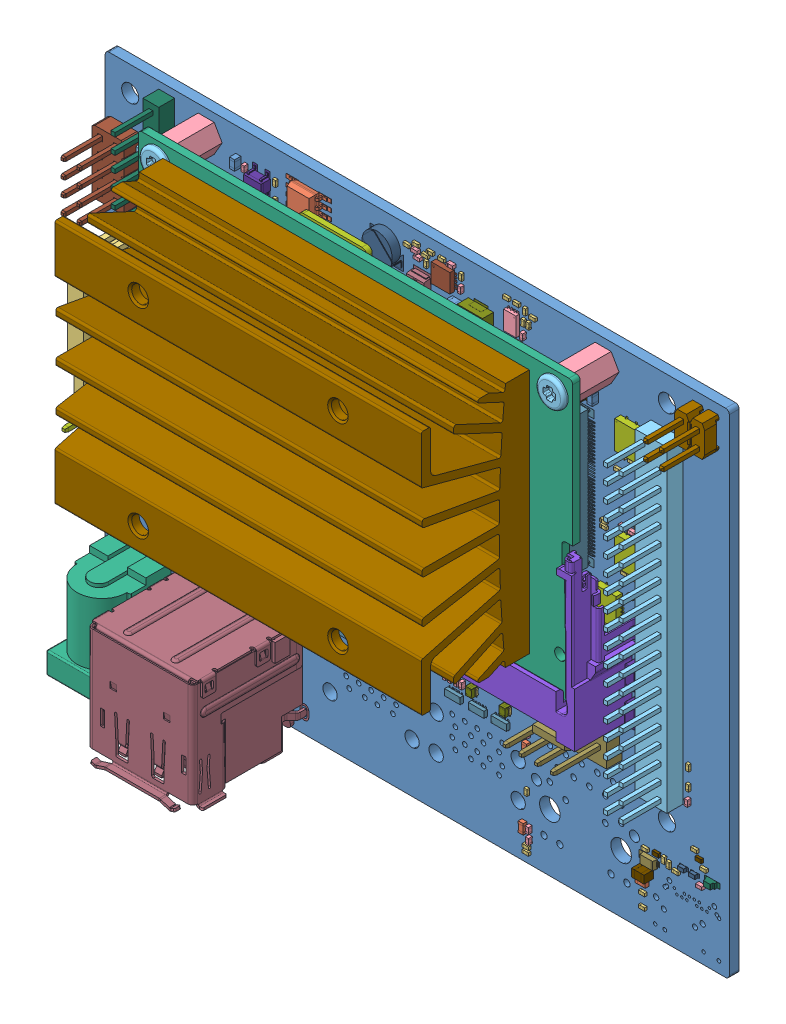
SolidWorks assembly P3450_P3449_A02_P3448_A02, configuration Défaut. Lengths in mm.
Overall size (100 81.03 30.21).
395 component instances, 66 part files, 0 mates.
Components (placement in the parent):
- 142-13449-1000-A02_ASM-1: 142-13449-1000-A02_ASM [Défaut] at origin size (100 81.03 22.88)
  - 142-13449-1000-A02-1: 142-13449-1000-A02 [Défaut] at origin size (100 79 1.57)
  - 315-1109-000_1-1: 315-1109-000_1 [Défaut] at (5.6 4.9 1.575) x (-1 0 0) z (0 0 1) size (4.5 3.5 0.8)
  - 0402_H040-1: 0402_H040 [Défaut] at (8 -0.825 1.575) size (1 0.5 0.4)
  - 0402_H060-1: 0402_H060 [Défaut] at (1 5 1.575) x (0 -1 0) z (0 0 1) size (1 0.5 0.6)
  - 0402_H040-2: 0402_H040 [Défaut] at (9.9 -0.3 1.575) size (1 0.5 0.4)
  - 0402_H040-3: 0402_H040 [Défaut] at (8.296 51.194 1.575) x (-1 0 0) z (0 0 1) size (1 0.5 0.4)
  - 0402_H040-4: 0402_H040 [Défaut] at (76.2 36.9 1.575) x (-1 0 0) z (0 0 1) size (1 0.5 0.4)
  - 0402_H040-5: 0402_H040 [Défaut] at (37.8 2.87 1.575) x (0 -1 0) z (0 0 1) size (1 0.5 0.4)
  - 0402_H040-6: 0402_H040 [Défaut] at (38.6 2.87 1.575) x (0 -1 0) z (0 0 1) size (1 0.5 0.4)
  - 0402_H060-2: 0402_H060 [Défaut] at (14.2 7.7 1.575) x (0 -1 0) z (0 0 1) size (1 0.5 0.6)
  - 0402_H040-7: 0402_H040 [Défaut] at (64 27.5 1.575) x (-1 0 0) z (0 0 1) size (1 0.5 0.4)
  - 0402_H060-3: 0402_H060 [Défaut] at (18.6 43.15 1.575) x (-1 0 0) z (0 0 1) size (1 0.5 0.6)
  - 0402_H060-4: 0402_H060 [Défaut] at (65.5 52.8 1.575) x (0 1 0) z (0 0 1) size (1 0.5 0.6)
  - 0402_H060-5: 0402_H060 [Défaut] at (64 28.4 1.575) x (-1 0 0) z (0 0 1) size (1 0.5 0.6)
  - 0402_H040-8: 0402_H040 [Défaut] at (60.95 25.85 1.575) size (1 0.5 0.4)
  - 0402_H060-6: 0402_H060 [Défaut] at (17.3 7.7 1.575) x (0 -1 0) z (0 0 1) size (1 0.5 0.6)
  - 0402_H060-7: 0402_H060 [Défaut] at (18.6 7.7 1.575) x (0 -1 0) z (0 0 1) size (1 0.5 0.6)
  - 0402_H060-8: 0402_H060 [Défaut] at (12.9 7.7 1.575) x (0 -1 0) z (0 0 1) size (1 0.5 0.6)
  - 0402_H060-9: 0402_H060 [Défaut] at (80.9 37.7 1.575) x (-1 0 0) z (0 0 1) size (1 0.5 0.6)
  - 0402_H040-9: 0402_H040 [Défaut] at (79.5 31.3 1.575) size (1 0.5 0.4)
  - 0402_H040-10: 0402_H040 [Défaut] at (81 31.3 1.575) x (-1 0 0) z (0 0 1) size (1 0.5 0.4)
  - 0402_H060-10: 0402_H060 [Défaut] at (79.3 37.7 1.575) size (1 0.5 0.6)
  - 0402_H060-11: 0402_H060 [Défaut] at (74.8 4.05 1.575) x (-1 0 0) z (0 0 1) size (1 0.5 0.6)
  - 0402_H040-11: 0402_H040 [Défaut] at (65.675 6.15 1.575) x (0 -1 0) z (0 0 1) size (1 0.5 0.4)
  - 0402_H060-12: 0402_H060 [Défaut] at (67.7 6.85 1.575) x (0 1 0) z (0 0 1) size (1 0.5 0.6)
  - 0402_H040-12: 0402_H040 [Défaut] at (64.475 5.8 1.575) x (-1 0 0) z (0 0 1) size (1 0.5 0.4)
  - 0402_H040-13: 0402_H040 [Défaut] at (67.725 5.325 1.575) x (0 1 0) z (0 0 1) size (1 0.5 0.4)
  - 0402_H060-13: 0402_H060 [Défaut] at (46.1 59.45 1.575) size (1 0.5 0.6)
  - 0402_H040-14: 0402_H040 [Défaut] at (44.65 59.45 1.575) size (1 0.5 0.4)
  - 0402_H040-15: 0402_H040 [Défaut] at (46.1 60.25 1.575) size (1 0.5 0.4)
  - 0402_H060-14: 0402_H060 [Défaut] at (53.35 57.7 1.575) x (0 -1 0) z (0 0 1) size (1 0.5 0.6)
  - 0402_H040-16: 0402_H040 [Défaut] at (47.6 59.45 1.575) size (1 0.5 0.4)
  - 0402_H040-17: 0402_H040 [Défaut] at (48.4 60.25 1.575) size (1 0.5 0.4)
  - 0402_H040-18: 0402_H040 [Défaut] at (47.7 58.325 1.575) x (0 1 0) z (0 0 1) size (1 0.5 0.4)
  - 0402_H060-15: 0402_H060 [Défaut] at (46.5 58.65 1.575) x (-1 0 0) z (0 0 1) size (1 0.5 0.6)
  - 0402_H060-16: 0402_H060 [Défaut] at (51.8 60.25 1.575) size (1 0.5 0.6)
  - 0402_H040-19: 0402_H040 [Défaut] at (53.35 59.4 1.575) x (0 -1 0) z (0 0 1) size (1 0.5 0.4)
  - 0402_H040-20: 0402_H040 [Défaut] at (50.2 60.25 1.575) x (-1 0 0) z (0 0 1) size (1 0.5 0.4)
  - 0402_H060-17: 0402_H060 [Défaut] at (18.6 43.95 1.575) x (-1 0 0) z (0 0 1) size (1 0.5 0.6)
  - 0402_H060-18: 0402_H060 [Défaut] at (52.75 2.9 1.575) x (0 -1 0) z (0 0 1) size (1 0.5 0.6)
  - 0402_H060-19: 0402_H060 [Défaut] at (22.35 47.4 1.575) x (-1 0 0) z (0 0 1) size (1 0.5 0.6)
  - 0402_H060-20: 0402_H060 [Défaut] at (20.55 47.4 1.575) x (-1 0 0) z (0 0 1) size (1 0.5 0.6)
  - 0402_H060-21: 0402_H060 [Défaut] at (21.95 34.55 1.575) x (0 -1 0) z (0 0 1) size (1 0.5 0.6)
  - 0402_H060-22: 0402_H060 [Défaut] at (21.05 34.55 1.575) x (0 -1 0) z (0 0 1) size (1 0.5 0.6)
  - 0402_H060-23: 0402_H060 [Défaut] at (53.55 2.9 1.575) x (0 -1 0) z (0 0 1) size (1 0.5 0.6)
  - 0402_H060-24: 0402_H060 [Défaut] at (25.4 54 1.575) x (-1 0 0) z (0 0 1) size (1 0.5 0.6)
  - 0402_H060-25: 0402_H060 [Défaut] at (24 34.58 1.575) x (0 -1 0) z (0 0 1) size (1 0.5 0.6)
  - 0402_H040-21: 0402_H040 [Défaut] at (55.6 2.95 1.575) x (0 -1 0) z (0 0 1) size (1 0.5 0.4)
  - 0402_H040-22: 0402_H040 [Défaut] at (20.13 34.53 1.575) x (0 1 0) z (0 0 1) size (1 0.5 0.4)
  - 0402_H060-26: 0402_H060 [Défaut] at (18.4 35.15 1.575) x (0 1 0) z (0 0 1) size (1 0.5 0.6)
  - 0402_H060-27: 0402_H060 [Défaut] at (18.4 36.75 1.575) x (0 1 0) z (0 0 1) size (1 0.5 0.6)
  - 0402_H040-23: 0402_H040 [Défaut] at (39.6 2.87 1.575) x (0 -1 0) z (0 0 1) size (1 0.5 0.4)
  - 0402_H040-24: 0402_H040 [Défaut] at (40.4 2.87 1.575) x (0 -1 0) z (0 0 1) size (1 0.5 0.4)
  - 0402_H040-25: 0402_H040 [Défaut] at (60.95 2.95 1.575) x (0 -1 0) z (0 0 1) size (1 0.5 0.4)
  - 0402_H040-26: 0402_H040 [Défaut] at (60.15 2.95 1.575) x (0 -1 0) z (0 0 1) size (1 0.5 0.4)
  - 0402_H040-27: 0402_H040 [Défaut] at (54.8 2.95 1.575) x (0 -1 0) z (0 0 1) size (1 0.5 0.4)
  - 0402_H040-28: 0402_H040 [Défaut] at (31.6 54 1.575) size (1 0.5 0.4)
  - 0402_H040-29: 0402_H040 [Défaut] at (27.4 54 1.575) size (1 0.5 0.4)
  - 0402_H040-30: 0402_H040 [Défaut] at (29.6 54 1.575) x (-1 0 0) z (0 0 1) size (1 0.5 0.4)
  - 0402_H040-31: 0402_H040 [Défaut] at (63.775 -14.475 1.575) size (1 0.5 0.4)
  - 0402_H040-32: 0402_H040 [Défaut] at (63.775 -15.275 1.575) size (1 0.5 0.4)
  - 0402_H040-33: 0402_H040 [Défaut] at (8.025 41.475 1.575) x (-1 0 0) z (0 0 1) size (1 0.5 0.4)
  - 0402_H060-28: 0402_H060 [Défaut] at (63.95 1.25 1.575) x (0 1 0) z (0 0 1) size (1 0.5 0.6)
  - 0402_H060-29: 0402_H060 [Défaut] at (2.95 54.05 1.575) x (0 1 0) z (0 0 1) size (1 0.5 0.6)
  - 0402_H040-34: 0402_H040 [Défaut] at (92.2 -3.45 1.575) x (-1 0 0) z (0 0 1) size (1 0.5 0.4)
  - 0402_H060-30: 0402_H060 [Défaut] at (32.85 7.7 1.575) x (0 -1 0) z (0 0 1) size (1 0.5 0.6)
  - 0402_H060-31: 0402_H060 [Défaut] at (27.25 7.7 1.575) x (0 -1 0) z (0 0 1) size (1 0.5 0.6)
  - 0402_H060-32: 0402_H060 [Défaut] at (31.25 7.7 1.575) x (0 -1 0) z (0 0 1) size (1 0.5 0.6)
  - 0402_H060-33: 0402_H060 [Défaut] at (28.85 7.7 1.575) x (0 -1 0) z (0 0 1) size (1 0.5 0.6)
  - 0402_H060-34: 0402_H060 [Défaut] at (32.05 7.7 1.575) x (0 -1 0) z (0 0 1) size (1 0.5 0.6)
  - 0402_H060-35: 0402_H060 [Défaut] at (28.05 7.7 1.575) x (0 -1 0) z (0 0 1) size (1 0.5 0.6)
  - 0402_H060-36: 0402_H060 [Défaut] at (30.45 7.7 1.575) x (0 -1 0) z (0 0 1) size (1 0.5 0.6)
  - 0402_H060-37: 0402_H060 [Défaut] at (29.65 7.7 1.575) x (0 -1 0) z (0 0 1) size (1 0.5 0.6)
  - 0402_H060-38: 0402_H060 [Défaut] at (24.65 6.41 1.575) x (0 -1 0) z (0 0 1) size (1 0.5 0.6)
  - 0402_H060-39: 0402_H060 [Défaut] at (25.85 6.41 1.575) x (0 -1 0) z (0 0 1) size (1 0.5 0.6)
  - 0402_H060-40: 0402_H060 [Défaut] at (4.2 36.5 1.575) x (0 1 0) z (0 0 1) size (1 0.5 0.6)
  - 0402_H060-41: 0402_H060 [Défaut] at (89.7 4.7 1.575) x (0 -1 0) z (0 0 1) size (1 0.5 0.6)
  - 0402_H060-42: 0402_H060 [Défaut] at (82.5 3.8 1.575) x (0 -1 0) z (0 0 1) size (1 0.5 0.6)
  - 0402_H060-43: 0402_H060 [Défaut] at (12.65 49.7 1.575) size (1 0.5 0.6)
  - 0402_H060-44: 0402_H060 [Défaut] at (11.2 50.15 1.575) x (0 -1 0) z (0 0 1) size (1 0.5 0.6)
  - 0402_H060-45: 0402_H060 [Défaut] at (26.5 34.55 1.575) x (0 -1 0) z (0 0 1) size (1 0.5 0.6)
  - 0402_H060-46: 0402_H060 [Défaut] at (29.9 34.5 1.575) x (0 -1 0) z (0 0 1) size (1 0.5 0.6)
  - 0402_H060-47: 0402_H060 [Défaut] at (31.7 40.15 1.575) x (0 1 0) z (0 0 1) size (1 0.5 0.6)
  - 0402_H060-48: 0402_H060 [Défaut] at (31.15 42.5 1.575) x (0 1 0) z (0 0 1) size (1 0.5 0.6)
  - 0402_H060-49: 0402_H060 [Défaut] at (19.2 47.05 1.575) x (0 1 0) z (0 0 1) size (1 0.5 0.6)
  - 0402_H060-50: 0402_H060 [Défaut] at (17.95 42 1.575) x (0 -1 0) z (0 0 1) size (1 0.5 0.6)
  - 0402_H060-51: 0402_H060 [Défaut] at (27.3 48.25 1.575) x (0 1 0) z (0 0 1) size (1 0.5 0.6)
  - 0402_H060-52: 0402_H060 [Défaut] at (31.7 37.85 1.575) x (0 -1 0) z (0 0 1) size (1 0.5 0.6)
  - 0402_H060-53: 0402_H060 [Défaut] at (29.6 48.35 1.575) x (0 1 0) z (0 0 1) size (1 0.5 0.6)
  - 0402_H060-54: 0402_H060 [Défaut] at (18.8 38.75 1.575) x (-1 0 0) z (0 0 1) size (1 0.5 0.6)
  - 0402_H060-55: 0402_H060 [Défaut] at (18.7 57.2 1.575) x (0 -1 0) z (0 0 1) size (1 0.5 0.6)
  - 0402_H060-56: 0402_H060 [Défaut] at (34.1 2.9 1.575) x (0 -1 0) z (0 0 1) size (1 0.5 0.6)
  - 0402_H060-57: 0402_H060 [Défaut] at (35.8 2.9 1.575) x (0 -1 0) z (0 0 1) size (1 0.5 0.6)
  - 0402_H060-58: 0402_H060 [Défaut] at (34.9 2.9 1.575) x (0 -1 0) z (0 0 1) size (1 0.5 0.6)
  - 0402_H060-59: 0402_H060 [Défaut] at (36.6 2.9 1.575) x (0 -1 0) z (0 0 1) size (1 0.5 0.6)
  - 0402_H060-60: 0402_H060 [Défaut] at (11.325 44.725 1.575) size (1 0.5 0.6)
  - 0402_H060-61: 0402_H060 [Défaut] at (50.95 2.9 1.575) x (0 -1 0) z (0 0 1) size (1 0.5 0.6)
  - 0402_H060-62: 0402_H060 [Défaut] at (51.75 2.9 1.575) x (0 -1 0) z (0 0 1) size (1 0.5 0.6)
  - 0402_H060-63: 0402_H060 [Défaut] at (11.55 39.7 1.575) size (1 0.5 0.6)
  - 0402_H060-64: 0402_H060 [Défaut] at (9.5 -8.5 1.575) x (-1 0 0) z (0 0 1) size (1 0.5 0.6)
  - 0402_H060-65: 0402_H060 [Défaut] at (61.35 38.05 1.575) x (0 -1 0) z (0 0 1) size (1 0.5 0.6)
  - 0402_H060-66: 0402_H060 [Défaut] at (60.55 38.05 1.575) x (0 -1 0) z (0 0 1) size (1 0.5 0.6)
  - 0402_H060-67: 0402_H060 [Défaut] at (29.3 25.65 1.575) x (0 -1 0) z (0 0 1) size (1 0.5 0.6)
  - 0402_H060-68: 0402_H060 [Défaut] at (63.3 56.2 1.575) x (0 1 0) z (0 0 1) size (1 0.5 0.6)
  - 0402_H060-69: 0402_H060 [Défaut] at (20.5 54.2 1.575) size (1 0.5 0.6)
  - 0402_H060-70: 0402_H060 [Défaut] at (60.1 32.15 1.575) x (0 1 0) z (0 0 1) size (1 0.5 0.6)
  - 0402_H060-71: 0402_H060 [Défaut] at (60.9 32.15 1.575) x (0 1 0) z (0 0 1) size (1 0.5 0.6)
  - 0402_H060-72: 0402_H060 [Défaut] at (18.6 44.85 1.575) size (1 0.5 0.6)
  - 0402_H060-73: 0402_H060 [Défaut] at (18.6 45.65 1.575) size (1 0.5 0.6)
  - 0402_H060-74: 0402_H060 [Défaut] at (18.1 27.25 1.575) size (1 0.5 0.6)
  - 0402_H060-75: 0402_H060 [Défaut] at (15.1 7.7 1.575) x (0 -1 0) z (0 0 1) size (1 0.5 0.6)
  - 0402_H060-76: 0402_H060 [Défaut] at (16.4 7.7 1.575) x (0 -1 0) z (0 0 1) size (1 0.5 0.6)
  - 0402_H060-77: 0402_H060 [Défaut] at (20.8 7.7 1.575) x (0 -1 0) z (0 0 1) size (1 0.5 0.6)
  - 0402_H060-78: 0402_H060 [Défaut] at (19.5 7.7 1.575) x (0 -1 0) z (0 0 1) size (1 0.5 0.6)
  - 0402_H060-79: 0402_H060 [Défaut] at (21.9 2.8 1.575) size (1 0.5 0.6)
  - 0402_H060-80: 0402_H060 [Défaut] at (12.75 29 1.575) size (1 0.5 0.6)
  - 0402_H060-81: 0402_H060 [Défaut] at (10.225 5.1 1.575) size (1 0.5 0.6)
  - 0402_H060-82: 0402_H060 [Défaut] at (22.8 27.65 1.575) x (0 1 0) z (0 0 1) size (1 0.5 0.6)
  - 0402_H060-83: 0402_H060 [Défaut] at (18.85 25.15 1.575) x (0 -1 0) z (0 0 1) size (1 0.5 0.6)
  - 0402_H060-84: 0402_H060 [Défaut] at (17.95 40.1 1.575) x (0 1 0) z (0 0 1) size (1 0.5 0.6)
  - 0402_H040-35: 0402_H040 [Défaut] at (20.8 6.2 1.575) x (0 1 0) z (0 0 1) size (1 0.5 0.4)
  - 0402_H040-36: 0402_H040 [Défaut] at (76 22.7 1.575) size (1 0.5 0.4)
  - 0402_H040-37: 0402_H040 [Défaut] at (23.7 26.85 1.575) x (0 1 0) z (0 0 1) size (1 0.5 0.4)
  - 0402_H040-38: 0402_H040 [Défaut] at (18 25.15 1.575) x (0 1 0) z (0 0 1) size (1 0.5 0.4)
  - 0402_H040-39: 0402_H040 [Défaut] at (17.3 28.25 1.575) x (-1 0 0) z (0 0 1) size (1 0.5 0.4)
  - 0402_H040-40: 0402_H040 [Défaut] at (13.15 4.2 1.575) x (0 -1 0) z (0 0 1) size (1 0.5 0.4)
  - 0402_H040-41: 0402_H040 [Défaut] at (17.2 30.15 1.575) x (0 -1 0) z (0 0 1) size (1 0.5 0.4)
  - 0402_H040-42: 0402_H040 [Défaut] at (14.2 6.2 1.575) x (0 1 0) z (0 0 1) size (1 0.5 0.4)
  - 0402_H040-43: 0402_H040 [Défaut] at (12.9 6.2 1.575) x (0 1 0) z (0 0 1) size (1 0.5 0.4)
  - 0402_H040-44: 0402_H040 [Défaut] at (15.1 6.2 1.575) x (0 1 0) z (0 0 1) size (1 0.5 0.4)
  - 0402_H040-45: 0402_H040 [Défaut] at (16.4 6.2 1.575) x (0 1 0) z (0 0 1) size (1 0.5 0.4)
  - 0402_H040-46: 0402_H040 [Défaut] at (19.5 6.2 1.575) x (0 1 0) z (0 0 1) size (1 0.5 0.4)
  - 0402_H040-47: 0402_H040 [Défaut] at (17.3 6.2 1.575) x (0 1 0) z (0 0 1) size (1 0.5 0.4)
  - 0402_H040-48: 0402_H040 [Défaut] at (18.6 6.2 1.575) x (0 1 0) z (0 0 1) size (1 0.5 0.4)
  - 0402_H040-49: 0402_H040 [Défaut] at (24.2 24.55 1.575) x (0 1 0) z (0 0 1) size (1 0.5 0.4)
  - 0402_H040-50: 0402_H040 [Défaut] at (23.5 54.9 1.575) x (0 1 0) z (0 0 1) size (1 0.5 0.4)
  - 0402_H040-51: 0402_H040 [Défaut] at (13.2 39.75 1.575) x (-1 0 0) z (0 0 1) size (1 0.5 0.4)
  - 0402_H040-52: 0402_H040 [Défaut] at (80.7 47.4 1.575) x (-1 0 0) z (0 0 1) size (1 0.5 0.4)
  - 0402_H040-53: 0402_H040 [Défaut] at (77.5 22.7 1.575) x (-1 0 0) z (0 0 1) size (1 0.5 0.4)
  - 0402_H040-54: 0402_H040 [Défaut] at (9.25 -12.75 1.575) x (-1 0 0) z (0 0 1) size (1 0.5 0.4)
  - 0402_H040-55: 0402_H040 [Défaut] at (9.25 -11.95 1.575) x (-1 0 0) z (0 0 1) size (1 0.5 0.4)
  - 0402_H040-56: 0402_H040 [Défaut] at (64.475 6.7 1.575) size (1 0.5 0.4)
  - 0402_H040-57: 0402_H040 [Défaut] at (29.3 24 1.575) x (0 1 0) z (0 0 1) size (1 0.5 0.4)
  - 0402_H040-58: 0402_H040 [Défaut] at (64.2 32.5 1.575) x (0 1 0) z (0 0 1) size (1 0.5 0.4)
  - 0402_H040-59: 0402_H040 [Défaut] at (64.15 47.45 1.575) x (0 -1 0) z (0 0 1) size (1 0.5 0.4)
  - 0402_H040-60: 0402_H040 [Défaut] at (64.2 31 1.575) x (0 -1 0) z (0 0 1) size (1 0.5 0.4)
  - 0402_H040-61: 0402_H040 [Défaut] at (76.2 36.1 1.575) x (-1 0 0) z (0 0 1) size (1 0.5 0.4)
  - 0402_H040-62: 0402_H040 [Défaut] at (78.4 45.15 1.575) size (1 0.5 0.4)
  - 0402_H040-63: 0402_H040 [Défaut] at (81.7 38.6 1.575) size (1 0.5 0.4)
  - 0402_H040-64: 0402_H040 [Défaut] at (81.7 39.4 1.575) size (1 0.5 0.4)
  - 0402_H040-65: 0402_H040 [Défaut] at (59.35 51.825 1.575) size (1 0.5 0.4)
  - 0402_H040-66: 0402_H040 [Défaut] at (60.825 51.825 1.575) x (-1 0 0) z (0 0 1) size (1 0.5 0.4)
  - 0402_H040-67: 0402_H040 [Défaut] at (89.7 9.5 1.575) x (0 1 0) z (0 0 1) size (1 0.5 0.4)
  - 0402_H040-68: 0402_H040 [Défaut] at (89.7 6.7 1.575) x (0 1 0) z (0 0 1) size (1 0.5 0.4)
  - 0402_H040-69: 0402_H040 [Défaut] at (3.9 34.2 1.575) x (0 -1 0) z (0 0 1) size (1 0.5 0.4)
  - 0402_H040-70: 0402_H040 [Défaut] at (5.1 35 1.575) x (0 1 0) z (0 0 1) size (1 0.5 0.4)
  - 0402_H040-71: 0402_H040 [Défaut] at (32.85 5.81 1.575) x (0 -1 0) z (0 0 1) size (1 0.5 0.4)
  - 0402_H040-72: 0402_H040 [Défaut] at (32.05 5.81 1.575) x (0 -1 0) z (0 0 1) size (1 0.5 0.4)
  - 0402_H040-73: 0402_H040 [Défaut] at (27.25 5.81 1.575) x (0 -1 0) z (0 0 1) size (1 0.5 0.4)
  - 0402_H040-74: 0402_H040 [Défaut] at (28.05 5.81 1.575) x (0 -1 0) z (0 0 1) size (1 0.5 0.4)
  - 0402_H040-75: 0402_H040 [Défaut] at (31.25 5.81 1.575) x (0 -1 0) z (0 0 1) size (1 0.5 0.4)
  - 0402_H040-76: 0402_H040 [Défaut] at (30.45 5.81 1.575) x (0 -1 0) z (0 0 1) size (1 0.5 0.4)
  - 0402_H040-77: 0402_H040 [Défaut] at (28.85 5.81 1.575) x (0 -1 0) z (0 0 1) size (1 0.5 0.4)
  - 0402_H040-78: 0402_H040 [Défaut] at (29.65 5.81 1.575) x (0 -1 0) z (0 0 1) size (1 0.5 0.4)
  - 0402_H040-79: 0402_H040 [Défaut] at (13.5 52.9 1.575) x (-1 0 0) z (0 0 1) size (1 0.5 0.4)
  - 0402_H040-80: 0402_H040 [Défaut] at (22.35 4 1.575) x (0 -1 0) z (0 0 1) size (1 0.5 0.4)
  - 0402_H040-81: 0402_H040 [Défaut] at (21.55 4 1.575) x (0 1 0) z (0 0 1) size (1 0.5 0.4)
  - 0402_H040-82: 0402_H040 [Défaut] at (25.85 4.9 1.575) x (0 -1 0) z (0 0 1) size (1 0.5 0.4)
  - 0402_H040-83: 0402_H040 [Défaut] at (11.8 52.9 1.575) size (1 0.5 0.4)
  - 0402_H040-84: 0402_H040 [Défaut] at (9.432 51.594 1.575) x (0 -1 0) z (0 0 1) size (1 0.5 0.4)
  - 0402_H040-85: 0402_H040 [Défaut] at (8.975 50.3 1.575) size (1 0.5 0.4)
  - 0402_H040-86: 0402_H040 [Défaut] at (82.8 -5.3 1.575) x (-1 0 0) z (0 0 1) size (1 0.5 0.4)
  - 0402_H040-87: 0402_H040 [Défaut] at (82.4 -11.6 1.575) x (-1 0 0) z (0 0 1) size (1 0.5 0.4)
  - 0402_H040-88: 0402_H040 [Défaut] at (22.8 26.05 1.575) x (0 1 0) z (0 0 1) size (1 0.5 0.4)
  - 0402_H040-89: 0402_H040 [Défaut] at (20.8 28.25 1.575) size (1 0.5 0.4)
  - 0402_H040-90: 0402_H040 [Défaut] at (20.8 24.65 1.575) x (-1 0 0) z (0 0 1) size (1 0.5 0.4)
  - 0402_H040-91: 0402_H040 [Défaut] at (18.1 26.45 1.575) size (1 0.5 0.4)
  - 0402_H040-92: 0402_H040 [Défaut] at (24.65 8.41 1.575) x (0 1 0) z (0 0 1) size (1 0.5 0.4)
  - 0402_H040-93: 0402_H040 [Défaut] at (25.85 8.41 1.575) x (0 1 0) z (0 0 1) size (1 0.5 0.4)
  - 0402_H040-94: 0402_H040 [Défaut] at (3.8 54.4 1.575) x (0 -1 0) z (0 0 1) size (1 0.5 0.4)
  - 0402_H040-95: 0402_H040 [Défaut] at (2.45 44.45 1.575) x (0 -1 0) z (0 0 1) size (1 0.5 0.4)
  - 0402_H040-96: 0402_H040 [Défaut] at (24.65 4.9 1.575) x (0 1 0) z (0 0 1) size (1 0.5 0.4)
  - 0402_H040-97: 0402_H040 [Défaut] at (22.15 7.6 1.575) x (-1 0 0) z (0 0 1) size (1 0.5 0.4)
  - 0402_H040-98: 0402_H040 [Défaut] at (79.2 47.4 1.575) size (1 0.5 0.4)
  - 0402_H040-99: 0402_H040 [Défaut] at (19 28.25 1.575) size (1 0.5 0.4)
  - 0402_H040-100: 0402_H040 [Défaut] at (9.65 9.7 1.575) x (0 -1 0) z (0 0 1) size (1 0.5 0.4)
  - 0402_H040-101: 0402_H040 [Défaut] at (28.35 34.45 1.575) x (0 1 0) z (0 0 1) size (1 0.5 0.4)
  - 0402_H040-102: 0402_H040 [Défaut] at (25.2 34.55 1.575) x (0 1 0) z (0 0 1) size (1 0.5 0.4)
  - 0402_H040-103: 0402_H040 [Défaut] at (10.625 6.35 1.575) x (0 -1 0) z (0 0 1) size (1 0.5 0.4)
  - 0402_H040-104: 0402_H040 [Défaut] at (9.825 6.35 1.575) x (0 1 0) z (0 0 1) size (1 0.5 0.4)
  - 0402_H040-105: 0402_H040 [Défaut] at (4.775 42.975 1.575) x (0 1 0) z (0 0 1) size (1 0.5 0.4)
  - 0402_H040-106: 0402_H040 [Défaut] at (19.8 32.9 1.575) x (-1 0 0) z (0 0 1) size (1 0.5 0.4)
  - 0402_H040-107: 0402_H040 [Défaut] at (22.35 24.65 1.575) x (-1 0 0) z (0 0 1) size (1 0.5 0.4)
  - 0402_H040-108: 0402_H040 [Défaut] at (62.4 54.7 1.575) size (1 0.5 0.4)
  - 0402_H040-109: 0402_H040 [Défaut] at (62.2 60.05 1.575) x (-1 0 0) z (0 0 1) size (1 0.5 0.4)
  - 0402_H040-110: 0402_H040 [Défaut] at (23.5 57.5 1.575) x (0 1 0) z (0 0 1) size (1 0.5 0.4)
  - 0402_H040-111: 0402_H040 [Défaut] at (12.8 44.725 1.575) size (1 0.5 0.4)
  - 0402_H040-112: 0402_H040 [Défaut] at (21.8 31.45 1.575) x (0 1 0) z (0 0 1) size (1 0.5 0.4)
  - 0402_H040-113: 0402_H040 [Défaut] at (19.25 34.55 1.575) x (0 1 0) z (0 0 1) size (1 0.5 0.4)
  - 0402_H040-114: 0402_H040 [Défaut] at (0.95 41.55 1.575) size (1 0.5 0.4)
  - 0402_H040-115: 0402_H040 [Défaut] at (64.1 58 1.575) x (0 1 0) z (0 0 1) size (1 0.5 0.4)
  - 0402_H040-116: 0402_H040 [Défaut] at (63.3 58 1.575) x (0 -1 0) z (0 0 1) size (1 0.5 0.4)
  - 0402_H040-117: 0402_H040 [Défaut] at (63.55 59.7 1.575) x (0 -1 0) z (0 0 1) size (1 0.5 0.4)
  - 0402_H060-85: 0402_H060 [Défaut] at (71.175 4 1.575) x (-1 0 0) z (0 0 1) size (1 0.5 0.6)
  - 0402_H040-118: 0402_H040 [Défaut] at (86.6 -5.6 1.575) x (0 1 0) z (0 0 1) size (1 0.5 0.4)
  - 0402_H040-119: 0402_H040 [Défaut] at (85.8 -5.3 1.575) x (0 1 0) z (0 0 1) size (1 0.5 0.4)
  - 0402_H040-120: 0402_H040 [Défaut] at (10.25 51.6 1.575) x (0 1 0) z (0 0 1) size (1 0.5 0.4)
  - 0402_H040-121: 0402_H040 [Défaut] at (80.5 28.55 1.575) size (1 0.5 0.4)
  - 0402_H040-122: 0402_H040 [Défaut] at (13.95 4.2 1.575) x (0 -1 0) z (0 0 1) size (1 0.5 0.4)
  - 0402_H040-123: 0402_H040 [Défaut] at (15.35 4.2 1.575) x (0 -1 0) z (0 0 1) size (1 0.5 0.4)
  - 0402_H040-124: 0402_H040 [Défaut] at (16.15 4.2 1.575) x (0 -1 0) z (0 0 1) size (1 0.5 0.4)
  - 0402_H040-125: 0402_H040 [Défaut] at (20.55 4.2 1.575) x (0 -1 0) z (0 0 1) size (1 0.5 0.4)
  - 0402_H040-126: 0402_H040 [Défaut] at (19.75 4.2 1.575) x (0 -1 0) z (0 0 1) size (1 0.5 0.4)
  - 0402_H040-127: 0402_H040 [Défaut] at (17.6 4.2 1.575) x (0 -1 0) z (0 0 1) size (1 0.5 0.4)
  - 0402_H040-128: 0402_H040 [Défaut] at (18.4 4.2 1.575) x (0 -1 0) z (0 0 1) size (1 0.5 0.4)
  - 0402_H060-86: 0402_H060 [Défaut] at (64.25 -13.325 1.575) x (0 -1 0) z (0 0 1) size (1 0.5 0.6)
  - 0402_H060-87: 0402_H060 [Défaut] at (64.225 -11.825 1.575) x (0 1 0) z (0 0 1) size (1 0.5 0.6)
  - 0402_H040-129: 0402_H040 [Défaut] at (63.8 -6.85 1.575) x (0 1 0) z (0 0 1) size (1 0.5 0.4)
  - 0402_H040-130: 0402_H040 [Défaut] at (81.7 41.95 1.575) size (1 0.5 0.4)
  - 0402_H040-131: 0402_H040 [Défaut] at (87.75 -6 1.575) x (-1 0 0) z (0 0 1) size (1 0.5 0.4)
  - 0402_H040-132: 0402_H040 [Défaut] at (82.4 -13.6 1.575) x (-1 0 0) z (0 0 1) size (1 0.5 0.4)
  - 0402_H060-88: 0402_H060 [Défaut] at (91.75 -5.95 1.575) size (1 0.5 0.6)
  - 0402_H040-133: 0402_H040 [Défaut] at (3.65 49.25 1.575) x (0 -1 0) z (0 0 1) size (1 0.5 0.4)
  - 0402_H040-134: 0402_H040 [Défaut] at (2.45 49.25 1.575) x (0 1 0) z (0 0 1) size (1 0.5 0.4)
  - 0402_H040-135: 0402_H040 [Défaut] at (90.75 -1.45 1.575) x (-1 0 0) z (0 0 1) size (1 0.5 0.4)
  - 0402_H040-136: 0402_H040 [Défaut] at (8.45 39.55 1.575) x (0 -1 0) z (0 0 1) size (1 0.5 0.4)
  - 0402_H060-89: 0402_H060 [Défaut] at (8.85 -5.25 1.575) x (-1 0 0) z (0 0 1) size (1 0.5 0.6)
  - 0402_H040-137: 0402_H040 [Défaut] at (18.6 32.55 1.575) x (0 1 0) z (0 0 1) size (1 0.5 0.4)
  - 0402_H060-90: 0402_H060 [Défaut] at (4.5 44.45 1.575) x (0 1 0) z (0 0 1) size (1 0.5 0.6)
  - 0402_H040-138: 0402_H040 [Défaut] at (8.35 2.75 1.575) size (1 0.5 0.4)
  - 0402_H040-139: 0402_H040 [Défaut] at (9.4 1.95 1.575) size (1 0.5 0.4)
  - 0402_H040-140: 0402_H040 [Défaut] at (8.2 1.55 1.575) x (0 1 0) z (0 0 1) size (1 0.5 0.4)
  - 0402_H060-91: 0402_H060 [Défaut] at (8.5 3.875 1.575) x (0 -1 0) z (0 0 1) size (1 0.5 0.6)
  - 0402_H060-92: 0402_H060 [Défaut] at (-0.8 41.5 1.575) x (-1 0 0) z (0 0 1) size (1 0.5 0.6)
  - 0402_H040-141: 0402_H040 [Défaut] at (-1.35 7.75 1.575) size (1 0.5 0.4)
  - 0402_H040-142: 0402_H040 [Défaut] at (8 0.425 1.575) size (1 0.5 0.4)
  - 0402_H040-143: 0402_H040 [Défaut] at (67.9 4.025 1.575) x (-1 0 0) z (0 0 1) size (1 0.5 0.4)
  - 0402_H040-144: 0402_H040 [Défaut] at (60.6 60.05 1.575) x (-1 0 0) z (0 0 1) size (1 0.5 0.4)
  - 0402_H040-145: 0402_H040 [Défaut] at (72.85 4 1.575) x (-1 0 0) z (0 0 1) size (1 0.5 0.4)
  - 0402_H040-146: 0402_H040 [Défaut] at (64.8 59.35 1.575) size (1 0.5 0.4)
  - 0402_H040-147: 0402_H040 [Défaut] at (7.2 7.3 1.575) size (1 0.5 0.4)
  - 0402_H040-148: 0402_H040 [Défaut] at (8.5 5.35 1.575) x (0 1 0) z (0 0 1) size (1 0.5 0.4)
  - 0402_H040-149: 0402_H040 [Défaut] at (8.475 7.075 1.575) x (0 1 0) z (0 0 1) size (1 0.5 0.4)
  - VIRTUAL_SHORT-1: VIRTUAL_SHORT [Défaut] at (23.5 32.9 1.575) x (0 1 0) z (0 0 1) size (0.25 0.25 1)
  - VIRTUAL_SHORT-2: VIRTUAL_SHORT [Défaut] at (26.85 32.85 1.575) x (0 1 0) z (0 0 1) size (0.25 0.25 1)
  - VIRTUAL_SHORT-3: VIRTUAL_SHORT [Défaut] at (30.6 33.8 1.575) x (0 1 0) z (0 0 1) size (0.25 0.25 1)
  - VIRTUAL_SHORT-4: VIRTUAL_SHORT [Défaut] at (32.65 39.75 1.575) x (-1 0 0) z (0 0 1) size (0.25 0.25 1)
  - VIRTUAL_SHORT-5: VIRTUAL_SHORT [Défaut] at (31.85 42.1 1.575) x (-1 0 0) z (0 0 1) size (0.25 0.25 1)
  - VIRTUAL_SHORT-6: VIRTUAL_SHORT [Défaut] at (17.35 42.4 1.575) size (0.25 0.25 1)
  - VIRTUAL_SHORT-7: VIRTUAL_SHORT [Défaut] at (18.6 46.6 1.575) size (0.25 0.25 1)
  - VIRTUAL_SHORT-8: VIRTUAL_SHORT [Défaut] at (20.9 32.9 1.575) x (0 1 0) z (0 0 1) size (0.25 0.25 1)
  - VIRTUAL_SHORT-9: VIRTUAL_SHORT [Défaut] at (28.6 48.25 1.575) x (0 -1 0) z (0 0 1) size (0.25 0.25 1)
  - VIRTUAL_SHORT-10: VIRTUAL_SHORT [Défaut] at (27.1 49.35 1.575) x (0 -1 0) z (0 0 1) size (0.25 0.25 1)
  - VIRTUAL_SHORT-11: VIRTUAL_SHORT [Défaut] at (22.1 32.95 1.575) x (-1 0 0) z (0 0 1) size (0.25 0.25 1)
  - VIRTUAL_SHORT-12: VIRTUAL_SHORT [Défaut] at (32.65 38.25 1.575) x (-1 0 0) z (0 0 1) size (0.25 0.25 1)
  - VIRTUAL_SHORT-13: VIRTUAL_SHORT [Défaut] at (30.3 48 1.575) x (-1 0 0) z (0 0 1) size (0.25 0.25 1)
  - VIRTUAL_SHORT-14: VIRTUAL_SHORT [Défaut] at (17.15 38.95 1.575) size (0.25 0.25 1)
  - VIRTUAL_SHORT-15: VIRTUAL_SHORT [Défaut] at (17.15 39.7 1.575) size (0.25 0.25 1)
  - VIRTUAL_SHORT-16: VIRTUAL_SHORT [Défaut] at (76.175 4.1 1.575) x (-1 0 0) z (0 0 1) size (0.25 0.25 1)
  - 064-0377-000_2-1: 064-0377-000_2 [Défaut] at (2 -4.75 1.575) x (0 -1 0) z (0 0 1) size (14.63 10.08 14.5)
  - 074-0117-000_2-1: 074-0117-000_2 [Défaut] at (0.254 14.3 1.575) size (5.08 2.54 11.66)
  - 090-0096-000_1-1: 090-0096-000_1 [Défaut] at (3.45 44.4 1.575) x (0 -1 0) z (0 0 1) size (1.2 0.6 0.4)
  - 090-0309-000_1-1: 090-0309-000_1 [Défaut] at (-1.65 8.7 1.575) x (-1 0 0) z (0 0 1) size (1.2 0.6 0.4)
  - 115-1232-000_2-1: 115-1232-000_2 [Défaut] at (1.25 6.5 1.575) x (-1 0 0) z (0 0 1) size (0.9 0.9 0.33)
  - 074-0102-000_4-1: 074-0102-000_4 [Défaut] at (0.254 44.36 1.575) x (0 1 0) z (0 0 1) size (10.16 5.08 11.6)
  - 064-0400-000_1-1: 064-0400-000_1 [Défaut] at (73.75 7.77 1.575) size (10.16 5.8 13.5)
  - MEC_STANDOFF_PTH_620C380P-1: MEC_STANDOFF_PTH_620C380P [Défaut] at (40.276 40.3 1.575) x (0 1 0) z (0 0 1) size (6.2 6.2 0.73)
  - 090-0231-000_1-1: 090-0231-000_1 [Défaut] at (35.3 0.7 1.575) x (-1 0 0) z (0 0 1) size (2.5 1.55 0.55)
  - 090-0231-000_1-2: 090-0231-000_1 [Défaut] at (52.25 0.7 1.575) x (-1 0 0) z (0 0 1) size (2.5 1.55 0.55)
  - 090-0231-000_1-3: 090-0231-000_1 [Défaut] at (56.05 0.7 1.575) size (2.5 1.55 0.55)
  - 090-0231-000_1-4: 090-0231-000_1 [Défaut] at (59.65 0.7 1.575) size (2.5 1.55 0.55)
  - 090-0231-000_1-5: 090-0231-000_1 [Défaut] at (39.1 0.7 1.575) size (2.5 1.55 0.55)
  - 090-0231-000_1-6: 090-0231-000_1 [Défaut] at (43.1 0.7 1.575) size (2.5 1.55 0.55)
  - 090-0231-000_1-7: 090-0231-000_1 [Défaut] at (14.6 1.8 1.575) size (2.5 1.55 0.55)
  - 090-0231-000_1-8: 090-0231-000_1 [Défaut] at (19.1 1.8 1.575) size (2.5 1.55 0.55)
  - 090-0231-000_1-9: 090-0231-000_1 [Défaut] at (22.5 1.4 1.575) size (2.5 1.55 0.55)
  - 090-0231-000_1-10: 090-0231-000_1 [Défaut] at (28.45 3.35 1.575) size (2.5 1.55 0.55)
  - 090-0231-000_1-11: 090-0231-000_1 [Défaut] at (31.65 3.35 1.575) size (2.5 1.55 0.55)
  - 074-0223-000_2-1: 074-0223-000_2 [Défaut] at (5.85 53.25 1.575) x (0 1 0) z (0 0 1) size (15.24 2.54 11.6)
  - 131-0832-000_2-1: 131-0832-000_2 [Défaut] at (56.3 54.7 1.575) x (0 -1 0) z (0 0 1) size (4.96 4.06 1.8)
  - 115-0836-000_1-1: 115-0836-000_1 [Défaut] at (21.1 56.6 1.575) size (2.9 3.58 1.45)
  - 115-0836-000_1-2: 115-0836-000_1 [Défaut] at (11.8 42.3 1.575) size (2.9 3.58 1.45)
  - 315-0620-000_1-1: 315-0620-000_1 [Défaut] at (72.1 53.4 1.575) x (0 -1 0) z (0 0 1) size (2.9 3.58 1.1)
  - 315-1062-000_1-1: 315-1062-000_1 [Défaut] at (26.8 25.15 1.575) x (0 -1 0) z (0 0 1) size (2.9 3.58 1.45)
  - 170-0285-000_1-1: 170-0285-000_1 [Défaut] at (28.72 57.28 1.575) x (0 1 0) z (0 0 1) size (4.9 7.21 1.75)
  - 115-0138-000_1-1: 115-0138-000_1 [Défaut] at (9.15 48.55 1.575) x (0 1 0) z (0 0 1) size (2 2.88 1.1)
  - 115-1821-000_1-1: 115-1821-000_1 [Défaut] at (3.3 40.8 1.575) x (-1 0 0) z (0 0 1) size (2 2.88 1.1)
  - 115-1821-000_1-2: 115-1821-000_1 [Défaut] at (6.25 39.55 1.575) x (0 -1 0) z (0 0 1) size (2 2.88 1.1)
  - 115-0742-000_2-1: 115-0742-000_2 [Défaut] at (3.05 46.85 1.575) size (2 2.88 1.1)
  - 115-0742-000_2-2: 115-0742-000_2 [Défaut] at (3.05 51.65 1.575) x (-1 0 0) z (0 0 1) size (2 2.88 1.1)
  - 115-1821-000_1-3: 115-1821-000_1 [Défaut] at (59.6 27.6 1.575) x (0 1 0) z (0 0 1) size (2 2.88 1.1)
  - 091-0022-000_1-1: 091-0022-000_1 [Défaut] at (-0.95 5.7 1.575) size (2 2.51 1.1)
  - 091-0023-000_1-1: 091-0023-000_1 [Défaut] at (15.25 29.9 1.575) x (0 -1 0) z (0 0 1) size (2 2.51 1.1)
  - 080-1656-000_3-1: 080-1656-000_3 [Défaut] at (44 16.6 1.575) x (-1 0 0) z (0 0 1) size (77.5 25.85 9.66)
  - 090-0243-000_1-1: 090-0243-000_1 [Défaut] at (8.5 -4.1 1.575) x (-1 0 0) z (0 0 1) size (1.41 0.61 0.45)
  - 090-0243-000_1-2: 090-0243-000_1 [Défaut] at (9.95 -3.7 1.575) x (0 1 0) z (0 0 1) size (1.41 0.61 0.45)
  - 090-0243-000_1-3: 090-0243-000_1 [Défaut] at (9.5 -10.95 1.575) x (-1 0 0) z (0 0 1) size (1.41 0.61 0.45)
  - 090-0243-000_1-4: 090-0243-000_1 [Défaut] at (9.8 -6.25 1.575) x (-1 0 0) z (0 0 1) size (1.41 0.61 0.45)
  - 090-0243-000_1-5: 090-0243-000_1 [Défaut] at (9.5 -9.5 1.575) x (-1 0 0) z (0 0 1) size (1.41 0.61 0.45)
  - 090-0172-000_1-1: 090-0172-000_1 [Défaut] at (90.6 -5 1.575) size (1.41 0.61 0.55)
  - 090-0172-000_1-2: 090-0172-000_1 [Défaut] at (88.8 -5 1.575) x (-1 0 0) z (0 0 1) size (1.41 0.61 0.55)
  - 115-2177-000_2-1: 115-2177-000_2 [Défaut] at (12.7 51.35 1.575) x (0 1 0) z (0 0 1) size (1.8 1.71 0.4)
  - 090-0233-000_1-1: 090-0233-000_1 [Défaut] at (83.5 -6.6 1.575) size (3.3 1.3 0.74)
  - 064-0374-000_2-1: 064-0374-000_2 [Défaut] at (19.75 -9.65 1.575) size (18.1 18.55 21.85)
  - 115-2628-000_3-1: 115-2628-000_3 [Défaut] at (25.2 41.2 1.575) size (9.5 9.5 0.9)
  - 092-0073-000_1-1: 092-0073-000_1 [Défaut] at (93.35 -4.75 1.575) x (-1 0 0) z (0 0 1) size (2.46 0.81 0.9)
  - IND_SMD_0402_H060-1: IND_SMD_0402_H060 [Défaut] at (12.85 29.9 1.575) x (-1 0 0) z (0 0 1) size (1 0.5 0.6)
  - 1206_H190-1: 1206_H190 [Défaut] at (82 18.8 1.575) x (0 1 0) z (0 0 1) size (3.22 1.64 1.94)
  - 1206_H190-2: 1206_H190 [Défaut] at (81.95 13.5 1.575) x (0 -1 0) z (0 0 1) size (3.22 1.64 1.94)
  - 300-0868-000_3-1: 300-0868-000_3 [Défaut] at (69.6 4 1.575) x (-1 0 0) z (0 0 1) size (1 0.6 0.4)
  - 300-0868-000_3-2: 300-0868-000_3 [Défaut] at (9.55 0.95 1.575) size (1 0.6 0.4)
  - 300-0868-000_3-3: 300-0868-000_3 [Défaut] at (19.6 31.45 1.575) x (0 -1 0) z (0 0 1) size (1 0.6 0.4)
  - 300-0868-000_3-4: 300-0868-000_3 [Défaut] at (91.45 -2.45 1.575) x (-1 0 0) z (0 0 1) size (1 0.6 0.4)
  - 300-0868-000_3-5: 300-0868-000_3 [Défaut] at (84.6 -5.1 1.575) size (1 0.6 0.4)
  - 300-0868-000_3-6: 300-0868-000_3 [Défaut] at (66.725 5.875 1.575) x (0 -1 0) z (0 0 1) size (1 0.6 0.4)
  - 300-0868-000_3-7: 300-0868-000_3 [Défaut] at (20.8 31.45 1.575) x (0 -1 0) z (0 0 1) size (1 0.6 0.4)
  - 300-0868-000_3-8: 300-0868-000_3 [Défaut] at (62.9 31.35 1.575) x (-1 0 0) z (0 0 1) size (1 0.6 0.4)
  - 300-0868-000_3-9: 300-0868-000_3 [Défaut] at (65.475 4.8 1.575) x (-1 0 0) z (0 0 1) size (1 0.6 0.4)
  - 300-0868-000_3-10: 300-0868-000_3 [Défaut] at (63.9 33.85 1.575) x (-1 0 0) z (0 0 1) size (1 0.6 0.4)
  - 300-0868-000_3-11: 300-0868-000_3 [Défaut] at (15.65 27.9 1.575) size (1 0.6 0.4)
  - 300-0868-000_3-12: 300-0868-000_3 [Défaut] at (11.8 6.1 1.575) x (0 1 0) z (0 0 1) size (1 0.6 0.4)
  - 300-0868-000_3-13: 300-0868-000_3 [Défaut] at (22.1 6.25 1.575) x (0 1 0) z (0 0 1) size (1 0.6 0.4)
  - 300-0869-000_3-1: 300-0869-000_3 [Défaut] at (9.65 8.1 1.575) x (0 -1 0) z (0 0 1) size (1 0.6 0.53)
  - 300-0402-000_1-1: 300-0402-000_1 [Défaut] at (20.8 26.45 1.575) x (0 -1 0) z (0 0 1) size (2 2.69 1.1)
  - 300-0560-000_1-1: 300-0560-000_1 [Défaut] at (6.8 43.65 1.575) x (-1 0 0) z (0 0 1) size (2 2.69 1.1)
  - 174-0159-000_2-1: 174-0159-000_2 [Défaut] at (61.49 57.15 1.575) x (-1 0 0) z (0 0 1) size (2 3.52 0.6)
  - 074-0221-000_3-1: 074-0221-000_3 [Défaut] at (86 29 1.575) x (0 1 0) z (0 0 1) size (50.8 5.08 11.6)
  - 2016MM_H100-1: 2016MM_H100 [Défaut] at (24.5 49.25 1.575) x (0 1 0) z (0 0 1) size (2.02 1.6 1.02)
  - 115-1921-000_3-1: 115-1921-000_3 [Défaut] at (80.45 50.52 1.575) x (0 -1 0) z (0 0 1) size (5 4 1)
  - 115-1921-000_3-2: 115-1921-000_3 [Défaut] at (80.4 34.5 1.575) x (0 -1 0) z (0 0 1) size (5 4 1)
  - 115-1921-000_3-3: 115-1921-000_3 [Défaut] at (77.2 25.9 1.575) x (0 -1 0) z (0 0 1) size (5 4 1)
  - 085-0328-000_2-1: 085-0328-000_2 [Défaut] at (16.28 36.32 1.575) x (0 -1 0) z (0 0 1) size (3.81 2.5 0.6)
  - 074-0216-000_2-1: 074-0216-000_2 [Défaut] at (92.14 58 1.575) x (-1 0 0) z (0 0 1) size (4.83 5 11.5)
  - 060-0002-000_1-1: 060-0002-000_1 [Défaut] at (41.2 57.9 1.575) x (0 -1 0) z (0 0 1) size (5.1 5.4 1.68)
  - 316-0697-000_1-1: 316-0697-000_1 [Défaut] at (50.6 58.1 1.575) x (0 -1 0) z (0 0 1) size (3 3.72 0.8)
  - 032-0256-000_1-1: 032-0256-000_1 [Défaut] at (5.925 9.425 1.575) size (4.22 2.82 2)
  - 041-0092-000_1-1: 041-0092-000_1 [Défaut] at (46.9 54.9 1.575) x (0 -1 0) z (0 0 1) size (4.22 2.82 1.2)
  - 080-1243-000_3-1: 080-1243-000_3 [Défaut] at (69.9 40.3 1.575) x (0 -1 0) z (0 0 1) size (21.9 9.1 4.8)
  - 102-0066-000_2-1: 102-0066-000_2 [Défaut] at (18 4.2 1.575) size (1 1.86 0.61)
  - 102-0066-000_2-2: 102-0066-000_2 [Défaut] at (13.55 4.2 1.575) size (1 1.86 0.61)
  - 102-0066-000_2-3: 102-0066-000_2 [Défaut] at (32.45 5.81 1.575) size (1 1.86 0.61)
  - 102-0066-000_2-4: 102-0066-000_2 [Défaut] at (27.65 5.81 1.575) size (1 1.86 0.61)
  - 102-0066-000_2-5: 102-0066-000_2 [Défaut] at (20.15 4.2 1.575) size (1 1.86 0.61)
  - 102-0066-000_2-6: 102-0066-000_2 [Défaut] at (15.75 4.2 1.575) size (1 1.86 0.61)
  - 102-0066-000_2-7: 102-0066-000_2 [Défaut] at (29.25 5.81 1.575) size (1 1.86 0.61)
  - 102-0066-000_2-8: 102-0066-000_2 [Défaut] at (30.85 5.81 1.575) size (1 1.86 0.61)
  - 102-0037-000_1-1: 102-0037-000_1 [Défaut] at (55.2 2.95 1.575) x (-1 0 0) z (0 0 1) size (1 1.86 0.91)
  - 102-0037-000_1-2: 102-0037-000_1 [Défaut] at (39.99 2.87 1.575) x (-1 0 0) z (0 0 1) size (1 1.86 0.91)
  - 102-0037-000_1-3: 102-0037-000_1 [Défaut] at (60.55 2.95 1.575) x (-1 0 0) z (0 0 1) size (1 1.86 0.91)
  - 102-0037-000_1-4: 102-0037-000_1 [Défaut] at (38.22 2.87 1.575) x (-1 0 0) z (0 0 1) size (1 1.86 0.91)
  - 0805_H140-1: 0805_H140 [Défaut] at (8.1 -2.1 1.575) size (2.02 1.27 1.42)
  - 0805_H150-1: 0805_H150 [Défaut] at (82.9 -8.4 1.575) x (-1 0 0) z (0 0 1) size (2.01 1.25 1.5)
  - 0603_H100-1: 0603_H100 [Défaut] at (6.1 41.525 1.575) x (-1 0 0) z (0 0 1) size (1.6 0.81 1)
  - 0603_H060-1: 0603_H060 [Défaut] at (63.25 -12 1.575) x (0 1 0) z (0 0 1) size (1.6 0.81 0.6)
  - 0603_H060-2: 0603_H060 [Défaut] at (63.8 -0.7 1.575) x (0 -1 0) z (0 0 1) size (1.6 0.81 0.6)
  - 0603_H060-3: 0603_H060 [Défaut] at (82.4 -10 1.575) x (-1 0 0) z (0 0 1) size (1.6 0.81 0.6)
  - 0603_H100-2: 0603_H100 [Défaut] at (9.486 -7.5 1.575) x (-1 0 0) z (0 0 1) size (1.6 0.81 1)
  - 0603_H100-3: 0603_H100 [Défaut] at (17.4 57.4 1.575) x (0 -1 0) z (0 0 1) size (1.6 0.81 1)
  - 0603_H100-4: 0603_H100 [Défaut] at (30.35 25.9 1.575) x (0 -1 0) z (0 0 1) size (1.6 0.81 1)
  - 0603_H100-5: 0603_H100 [Défaut] at (11.4 45.7 1.575) size (1.6 0.81 1)
  - 0603_H100-6: 0603_H100 [Défaut] at (3.2 43 1.575) size (1.6 0.81 1)
  - 0603_H100-7: 0603_H100 [Défaut] at (74.7 53.4 1.575) x (0 -1 0) z (0 0 1) size (1.6 0.81 1)
  - 0603_H100-8: 0603_H100 [Défaut] at (69.5 53.9 1.575) x (0 -1 0) z (0 0 1) size (1.6 0.81 1)
  - 0603_H100-9: 0603_H100 [Défaut] at (52.5 52.9 1.575) x (-1 0 0) z (0 0 1) size (1.6 0.81 1)
  - 0603_H100-10: 0603_H100 [Défaut] at (52.5 54.2 1.575) x (-1 0 0) z (0 0 1) size (1.6 0.81 1)
  - 0603_H100-11: 0603_H100 [Défaut] at (27.3 51.35 1.575) size (1.6 0.81 1)
  - 0603_H100-12: 0603_H100 [Défaut] at (22.7 49.1 1.575) x (0 1 0) z (0 0 1) size (1.6 0.81 1)
  - 0603_H100-13: 0603_H100 [Défaut] at (26.2 48.8 1.575) x (0 1 0) z (0 0 1) size (1.6 0.81 1)
  - 0603_H100-14: 0603_H100 [Défaut] at (20.9 49.1 1.575) x (0 1 0) z (0 0 1) size (1.6 0.81 1)
  - 0603_H100-15: 0603_H100 [Défaut] at (65.5 27.4 1.575) x (0 -1 0) z (0 0 1) size (1.6 0.81 1)
  - 0603_H100-16: 0603_H100 [Défaut] at (63.8 52.2 1.575) x (-1 0 0) z (0 0 1) size (1.6 0.81 1)
  - 0603_H100-17: 0603_H100 [Défaut] at (52.5 55.4 1.575) x (-1 0 0) z (0 0 1) size (1.6 0.81 1)
  - 080-1669-000_2-1: 080-1669-000_2 [Défaut] at (0.2 29 1.575) x (0 -1 0) z (0 0 1) size (22.4 5.4 7.7)
- PORG_HEX_STANDOFF-1: PORG_HEX_STANDOFF [Défaut] at (75.8 58.5 8.17) x (-1 0 0) z (0 0 -1) size (5.14 4.45 6.57)
- PORG_HEX_STANDOFF-2: PORG_HEX_STANDOFF [Défaut] at (12.2 58.5 8.17) x (-1 0 0) z (0 0 -1) size (5.14 4.45 6.57)
- PORG_SYSTEM_SCREW-1: PORG_SYSTEM_SCREW [Défaut] at (12.2 58.5 3.73) size (4.55 4.55 4.53)
- PORG_SYSTEM_SCREW-2: PORG_SYSTEM_SCREW [Défaut] at (75.8 58.5 3.73) size (4.55 4.55 4.53)
- 244-63448-0000-000_ASM-1: 244-63448-0000-000_ASM [Défaut] at (11.2 22.5 8.2712) size (69.6 45 21.37)
  - 142-63448-1GEN_A00-1: 142-63448-1GEN_A00 [Défaut] at origin size (69.6 45 1.2)
  - 142-13448-1000-A02_ASM-1: 142-13448-1000-A02_ASM [Défaut] at origin size (23 37.02 4.04)
    - 080-0051-000_3-1: 080-0051-000_3 [Défaut] at (28.331 29.139 0) x (-1 0 0) z (0 0 -1) size (13.4 17 1.29)
    - TM670M-A2_1-1: TM670M-A2_1 [Défaut] at (23.7 13.45 1.2) size (23 23 1.31)
  - 142-13448-1000-A02-SKU0000_ASM-1: 142-13448-1000-A02-SKU0000_ASM [Défaut] at origin size (23 23 1.31)
    - TM670M-A2_1-1: TM670M-A2_1 [Défaut] at (23.7 13.45 1.2) size (23 23 1.31)
  - PORG_HSK_ASSY_ASM-1: PORG_HSK_ASSY_ASM [Défaut] at (0 0 4.01) size (58.7 39.4 17.3)
    - PORG_HEAT_SINK-1: PORG_HEAT_SINK [Défaut] at origin size (58.7 39.4 17.3)
  - PORG_LEAF_SPRING_DRAWN-1: PORG_LEAF_SPRING_DRAWN [Défaut] at (0 0 -0.4) x (1 0.000001 0) z (0 0 1) size (39.83 21.3 1.2)
  - PORG_LEAF_SPRING_SCREW-1: PORG_LEAF_SPRING_SCREW [Défaut] at (6.9871 5.9982 5.21) x (0 0 -1) z (0 1 0) size (6.41 4.7 4.7)
  - PORG_LEAF_SPRING_SCREW-2: PORG_LEAF_SPRING_SCREW [Défaut] at (6.9871 20.9018 5.21) x (0 0 -1) z (0 1 0) size (6.41 4.7 4.7)
  - PORG_LEAF_SPRING_SCREW-3: PORG_LEAF_SPRING_SCREW [Défaut] at (40.4129 20.9018 5.21) x (0 0 -1) z (0 1 0) size (6.41 4.7 4.7)
  - PORG_LEAF_SPRING_SCREW-4: PORG_LEAF_SPRING_SCREW [Défaut] at (40.4129 5.9982 5.21) x (0 0 -1) z (0 1 0) size (6.41 4.7 4.7)
- PORG_SYSTEM_SCREW-3: PORG_SYSTEM_SCREW [Défaut] at (75.8 58.5 5.67) x (-1 0 0) z (0 0 -1) size (4.55 4.55 4.53)
- PORG_SYSTEM_SCREW-4: PORG_SYSTEM_SCREW [Défaut] at (12.2 58.5 5.67) x (-1 0 0) z (0 0 -1) size (4.55 4.55 4.53)
- 155-0576-000-1: 155-0576-000 [Défaut] at (40.276 40.3 5.01) size (5 5 4.09)
